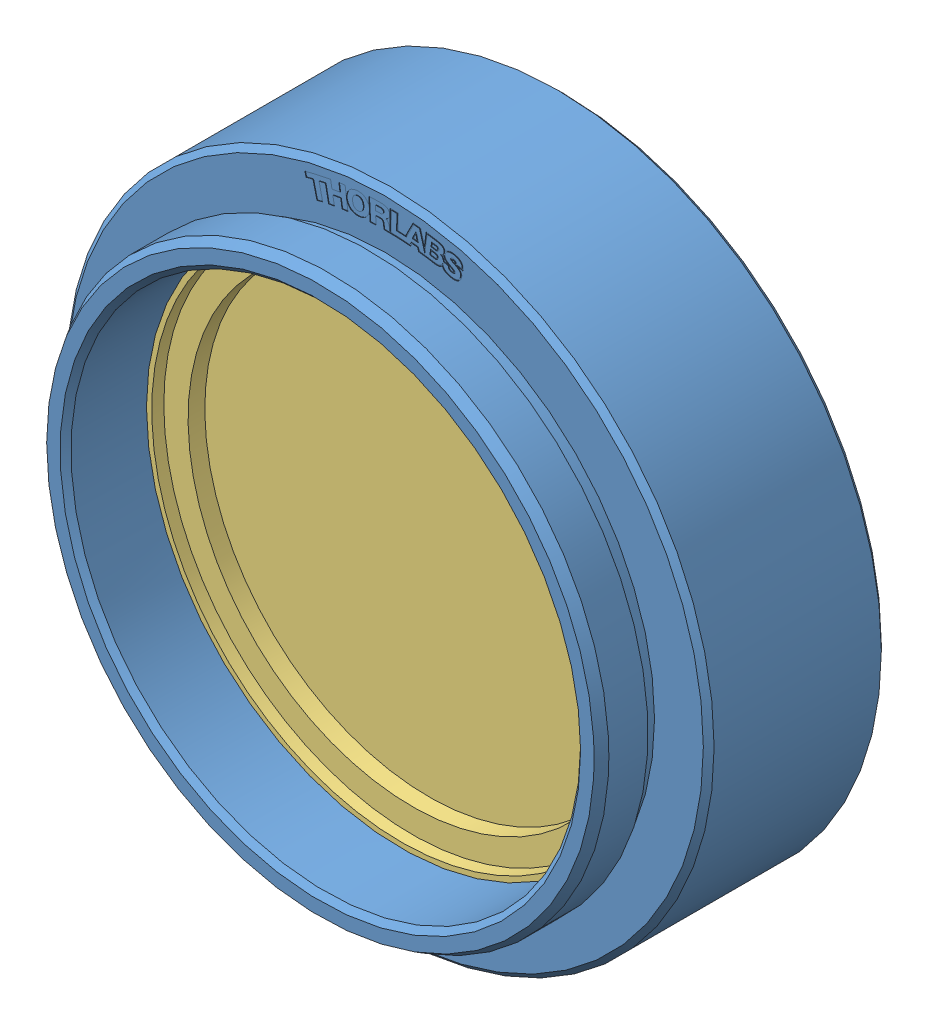
SolidWorks assembly Filter_Assembly, configuration Default. Lengths in mm.
Overall size (33.62 33.63 11.43).
3 component instances, 3 part files, 2 mates.
Components (placement in the parent):
- SM1L03-Solidworks-1: SM1L03-Solidworks [Default] at (9.4918 14.9499 16.3099) x (0 0 -1) z (1 0 0) size (11.43 30.48 30.48)
- FLH1030-10-Solidworks-1: FLH1030-10-Solidworks [Default] at (9.4918 14.9499 18.6799) x (0.991005 0.133826 0) z (0 0 1) size (25 25 3.5)
- FELH1000-Solidworks-1: FELH1000-Solidworks [Default] at (9.4918 14.9499 20.4299) x (0.891148 0.453712 0) z (0 0 1) size (25 25 3.5)
Mates (geometry in assembly coordinates):
- Concentric1: concentric aligned: circle of FLH1030-10-Solidworks-1; circle of FELH1000-Solidworks-1
- Concentric2: concentric aligned: circle of SM1L03-Solidworks-1; circle of FELH1000-Solidworks-1
